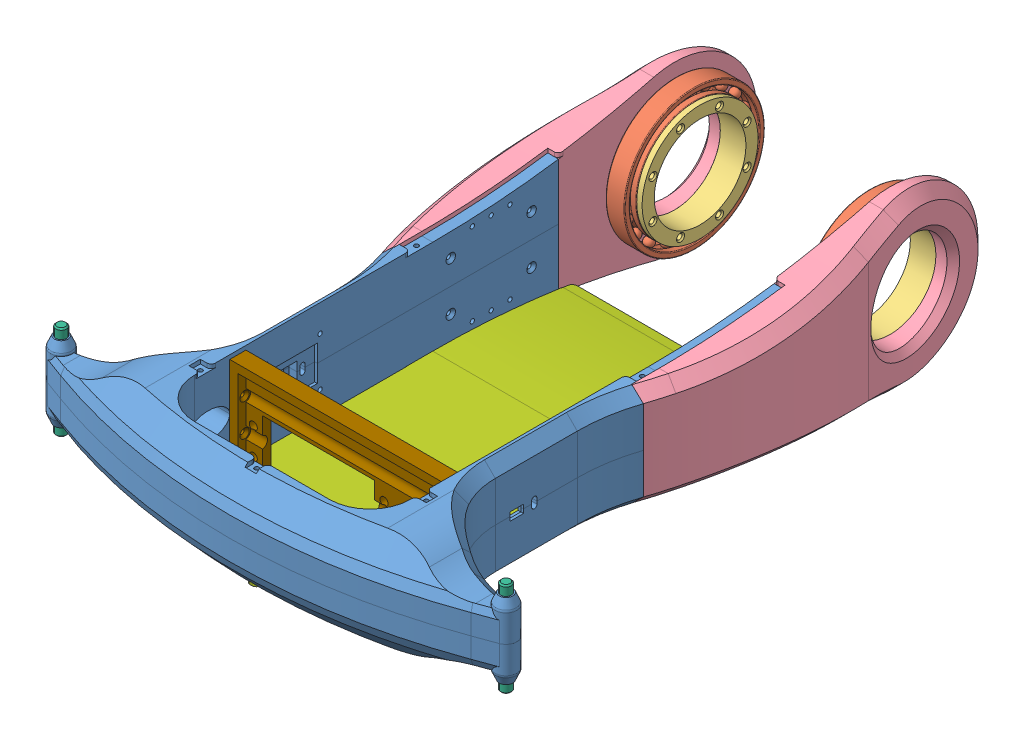
SolidWorks assembly Rahmen, configuration Standard. Lengths in mm.
Overall size (173 61 235.5).
18 component instances, 9 part files, 30 mates.
Components (placement in the parent):
- Rahmen-Vorne-2: Rahmen-Vorne [Standard] at (0 0 92.5) size (173 21.52 162)
- Rahmen-Vorne-3: Rahmen-Vorne [Standard] at (0 0 92.5) x (-1 0 0) z (0 0 1) size (173 21.52 162)
- Rahmen-Hinten-1: Rahmen-Hinten [Links] at (-36 0 -92.5) x (0 0 1) z (-1 0 0) size (130.5 61 25.5)
  - Kugellager - 61808 6808-1: Kugellager - 61808 6808 [Standard] at origin size (52 52 7)
  - Rad-Hinten-Aufnahme-1: Rad-Hinten-Aufnahme [Standard] at (0 0 3.5) size (43 43 9.5)
  - Rahmen-Hinten-1: Rahmen-Hinten [Standard] at (0 0 4) size (130.5 61 16.83)
  - Lager-Abstandsscheibe-1: Lager-Abstandsscheibe [Innen] at (0 0 3.75) size (43 43 0.5)
- Rahmen-Hinten-2: Rahmen-Hinten [Links] at (36 0 -92.5) x (0 0 1) z (1 0 0) size (130.5 61 25.5)
  - Kugellager - 61808 6808-1: Kugellager - 61808 6808 [Standard] at origin size (52 52 7)
  - Rad-Hinten-Aufnahme-1: Rad-Hinten-Aufnahme [Standard] at (0 0 3.5) size (43 43 9.5)
  - Rahmen-Hinten-1: Rahmen-Hinten [Standard] at (0 0 4) size (130.5 61 16.83)
  - Lager-Abstandsscheibe-1: Lager-Abstandsscheibe [Innen] at (0 0 3.75) size (43 43 0.5)
- Achse 4mm-1: Achse 4mm [L=35] at (-82.5 0 92.5) x (0 -1 0) z (0 0 -1) size (35 4 4)
- Achse 4mm-2: Achse 4mm [L=35] at (82.5 0 92.5) x (0 -1 0) z (0 0 -1) size (35 4 4)
- Blech-Abdeckung-1: Blech-Abdeckung [Mit Lüftungsöffnung] at (0 19 0) size (87.81 5.62 159.37) (hidden)
- Blech-Abdeckung-2: Blech-Abdeckung [Standard] at (0 -19 0) x (-1 0 0) z (0 0 1) size (87.99 5.62 159.37)
- Rahmen-Versteifung-Vorne-1: Rahmen-Versteifung-Vorne [Standard] at (0 0 99) x (-1 0 0) z (0 0 -1) size (50 30 1.5)
- Rahmen-Servo-1: Rahmen-Servo [Standard] at (0 0 66.5) size (80 35 11)
Mates (geometry in assembly coordinates):
- Symmetrisch1: symmetric aligned: plane of Rahmen-Hinten-1/Rahmen-Hinten-1 through (-40 0 -92.5) normal (1 0 0); plane of Rahmen-Hinten-2/Rahmen-Hinten-1 through (40 0 -92.5) normal (-1 0 0); plane of assembly through (0 0 0) normal (1 0 0)
- Deckungsgleich5: coincident aligned: plane of Rahmen-Hinten-1/Kugellager - 61808 6808-1; plane of assembly through (0 0 0) normal (0 1 0)
- Deckungsgleich6: coincident anti-aligned: plane of Rahmen-Hinten-2/Kugellager - 61808 6808-1; plane of assembly through (0 0 0) normal (0 1 0)
- Deckungsgleich7: coincident aligned: plane of Rahmen-Hinten-1/Kugellager - 61808 6808-1 through (-36 0 -92.5) normal (0 0 1); plane of Rahmen-Hinten-2/Kugellager - 61808 6808-1
- Konzentrisch1: concentric anti-aligned: cylinder of Rahmen-Vorne-2 through (-82.5 19 92.5) axis (0 -1 0) radius 2; cylinder of Achse 4mm-1 through (-82.5 -17.5 92.5) axis (0 1 0) radius 2
- Deckungsgleich15: coincident anti-aligned: plane of Achse 4mm-1; plane of assembly through (0 0 0) normal (0 1 0)
- Deckungsgleich16: coincident anti-aligned: plane of Rahmen-Vorne-2 through (0 0 92.5) normal (0 -1 0); plane of assembly through (0 0 0) normal (0 1 0)
- Deckungsgleich17: coincident anti-aligned: plane of Achse 4mm-2; plane of assembly through (0 0 0) normal (0 1 0)
- Deckungsgleich18: coincident anti-aligned: plane of Rahmen-Vorne-2 through (0 0 92.5) normal (0 -1 0); plane of Rahmen-Vorne-3 through (0 0 92.5) normal (0 1 0)
- Konzentrisch2: concentric aligned: cylinder of Achse 4mm-1 through (-82.5 -17.5 92.5) axis (0 1 0) radius 2; cylinder of Rahmen-Vorne-3 through (-82.5 -19 92.5) axis (0 1 0) radius 2
- Konzentrisch3: concentric anti-aligned: cylinder of Rahmen-Vorne-2 through (82.5 19 92.5) axis (0 -1 0) radius 2; cylinder of Achse 4mm-2 through (82.5 -17.5 92.5) axis (0 1 0) radius 2
- Konzentrisch4: concentric aligned: cylinder of Rahmen-Vorne-3 through (82.5 -19 92.5) axis (0 1 0) radius 2; cylinder of Achse 4mm-2 through (82.5 -17.5 92.5) axis (0 1 0) radius 2
- Deckungsgleich19: coincident aligned: plane of Rahmen-Vorne-2 through (0 0 92.5) normal (1 0 0); plane of assembly through (0 0 0) normal (1 0 0)
- Abstand3: distance = 185 mm aligned: plane of Rahmen-Vorne-2 through (0 0 92.5) normal (0 0 1); plane of Rahmen-Hinten-1/Kugellager - 61808 6808-1 through (-36 0 -92.5) normal (0 0 1)
- Symmetrisch3: symmetric anti-aligned: plane of Rahmen-Vorne-2 through (0 0 92.5) normal (0 0 1); plane of Rahmen-Hinten-1/Kugellager - 61808 6808-1 through (-36 0 -92.5) normal (0 0 1); plane of assembly through (0 0 0) normal (0 0 1)
- Abstand4: distance = 80 mm anti-aligned: plane of Rahmen-Hinten-1/Rahmen-Hinten-1 through (-40 0 -92.5) normal (1 0 0); plane of Rahmen-Hinten-2/Rahmen-Hinten-1 through (40 0 -92.5) normal (-1 0 0)
- Parallel1: parallel anti-aligned: plane of Achse 4mm-1 through (-82.5 0 92.5) normal (0 0 -1); plane of assembly through (0 0 0) normal (0 0 1)
- Parallel2: parallel anti-aligned: plane of Achse 4mm-2 through (82.5 0 92.5) normal (0 0 -1); plane of assembly through (0 0 0) normal (0 0 1)
- Deckungsgleich30: coincident aligned: plane of Rahmen-Vorne-2 through (0 19 92.5) normal (0 1 0); plane of Blech-Abdeckung-1 through (0 19 0) normal (0 1 0)
- Deckungsgleich31: coincident aligned: plane of Blech-Abdeckung-1 through (0 19 0) normal (1 0 0); plane of assembly through (0 0 0) normal (1 0 0)
- Deckungsgleich32: coincident aligned: plane of Blech-Abdeckung-1 through (0 19 0) normal (0 0 1); plane of assembly through (0 0 0) normal (0 0 1)
- Deckungsgleich33: coincident anti-aligned: plane of Rahmen-Vorne-3 through (0 -17.5 92.5) normal (0 -1 0); plane of Blech-Abdeckung-2 through (-41.6 -17.5 7.2) normal (0 1 0)
- Deckungsgleich34: coincident anti-aligned: plane of Blech-Abdeckung-2; plane of assembly through (0 0 0) normal (1 0 0)
- Deckungsgleich35: coincident aligned: plane of Blech-Abdeckung-2 through (0 -19 0) normal (0 0 1); plane of assembly through (0 0 0) normal (0 0 1)
- Deckungsgleich36: coincident anti-aligned: plane of Rahmen-Vorne-2 through (0 19 100.5) normal (0 0 -1); plane of Rahmen-Versteifung-Vorne-1 through (0 0 100.5) normal (0 0 1)
- Deckungsgleich37: coincident aligned: plane of Rahmen-Versteifung-Vorne-1; plane of assembly through (0 0 0) normal (0 1 0)
- Deckungsgleich38: coincident anti-aligned: plane of Rahmen-Versteifung-Vorne-1 through (0 0 99) normal (-1 0 0); plane of assembly through (0 0 0) normal (1 0 0)
- Deckungsgleich39: coincident aligned: plane of Rahmen-Servo-1 through (0 0 66.5) normal (0 1 0); plane of assembly through (0 0 0) normal (0 1 0)
- Deckungsgleich40: coincident: plane of Rahmen-Servo-1 through (0 0 66.5) normal (1 0 0); point of assembly
- Konzentrisch5: concentric aligned: cylinder of Rahmen-Vorne-2 through (-46.2627 6 70) axis (1 0 0) radius 0.8; cylinder of Rahmen-Servo-1 through (-37 6 70) axis (1 0 0) radius 0.8
